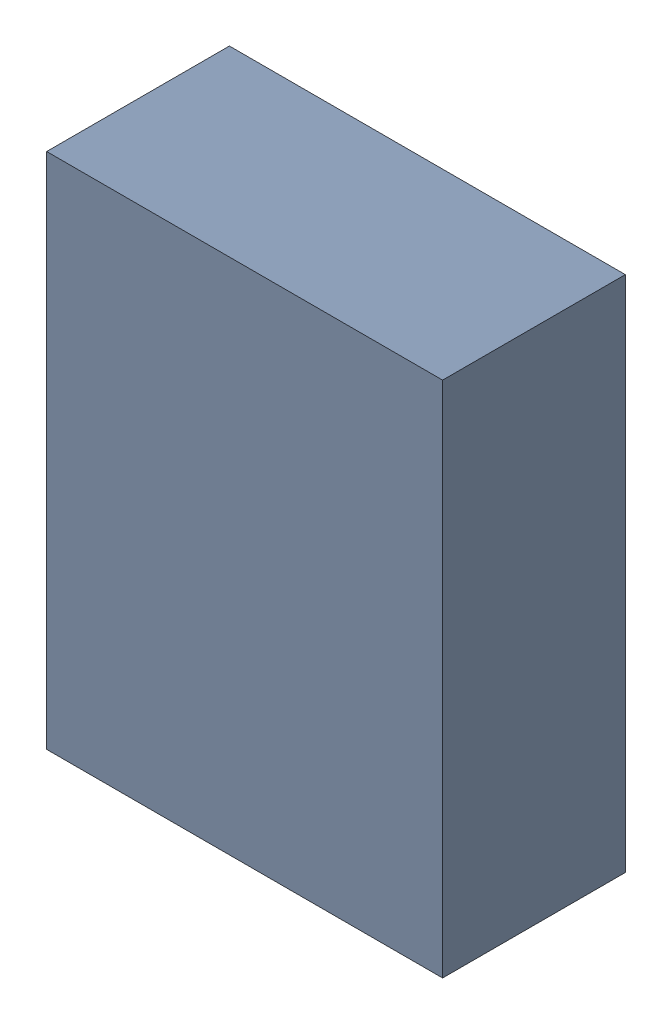
SolidWorks assembly U402PCB, configuration Default. Lengths in mm.
Overall size (1.3 1.7 0.6).
2 component instances, 1 part files, 0 mates.
Components (placement in the parent):
- 846487232-1: 846487232 [Default] at (121.5 103.6 0) size (1.3 1.7 0.6)
  - Extruded_47-1: Extruded_47 [Default] at origin size (1.3 1.7 0.6)
